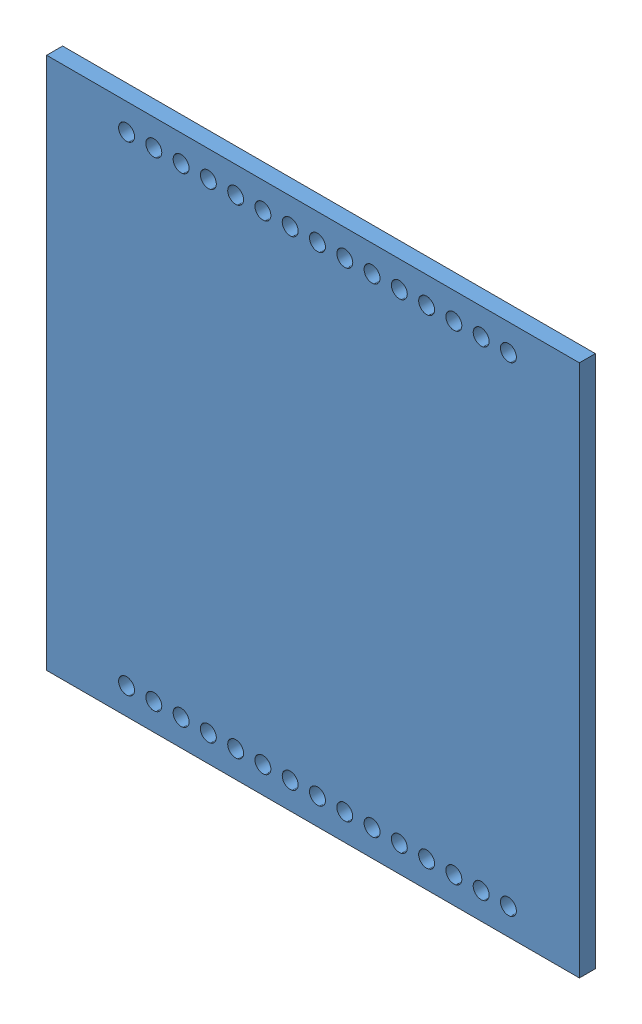
SolidWorks assembly idv pcb with headers, configuration Default. Lengths in mm.
Overall size (50 50 12.5).
3 component instances, 2 part files, 4 mates.
Components (placement in the parent):
- psb-1: psb [Default] at (15.9558 27.0682 38.3955) size (50 50 1.5)
- header pins short-1: header pins short [Default] at (-1.5442 49.5682 39.8955) x (1 0 0) z (0 0 -1) size (40 3 12.5)
- header pins short-2: header pins short [Default] at (-1.5442 4.5682 39.8955) x (1 0 0) z (0 0 -1) size (40 3 12.5)
Mates (geometry in assembly coordinates):
- Coincident1: coincident aligned: circle of psb-1; circle of header pins short-2
- Coincident2: coincident aligned: circle of psb-1; circle of header pins short-2
- Coincident3: coincident aligned: circle of psb-1; circle of header pins short-1
- Coincident4: coincident aligned: circle of psb-1; cylinder of header pins short-1 through (-1.5442 49.5682 35.8955) axis (0 0 1) radius 0.75
